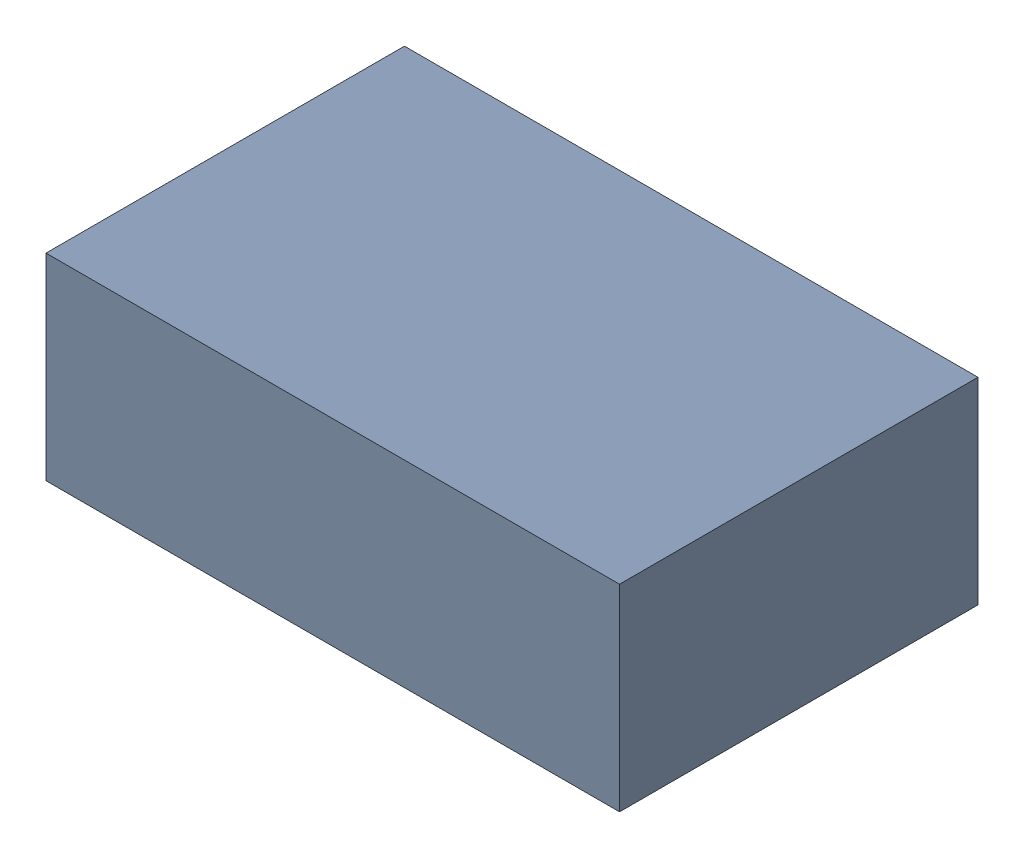
SolidWorks assembly C6, configuration Default. Lengths in mm.
Overall size (32 11 20).
2 component instances, 1 part files, 0 mates.
Components (placement in the parent):
- 809728768-1: 809728768 [Default] at (31.5903 107.188 0) size (32 11 20)
  - Extruded_4-1: Extruded_4 [Default] at origin size (32 11 20)
